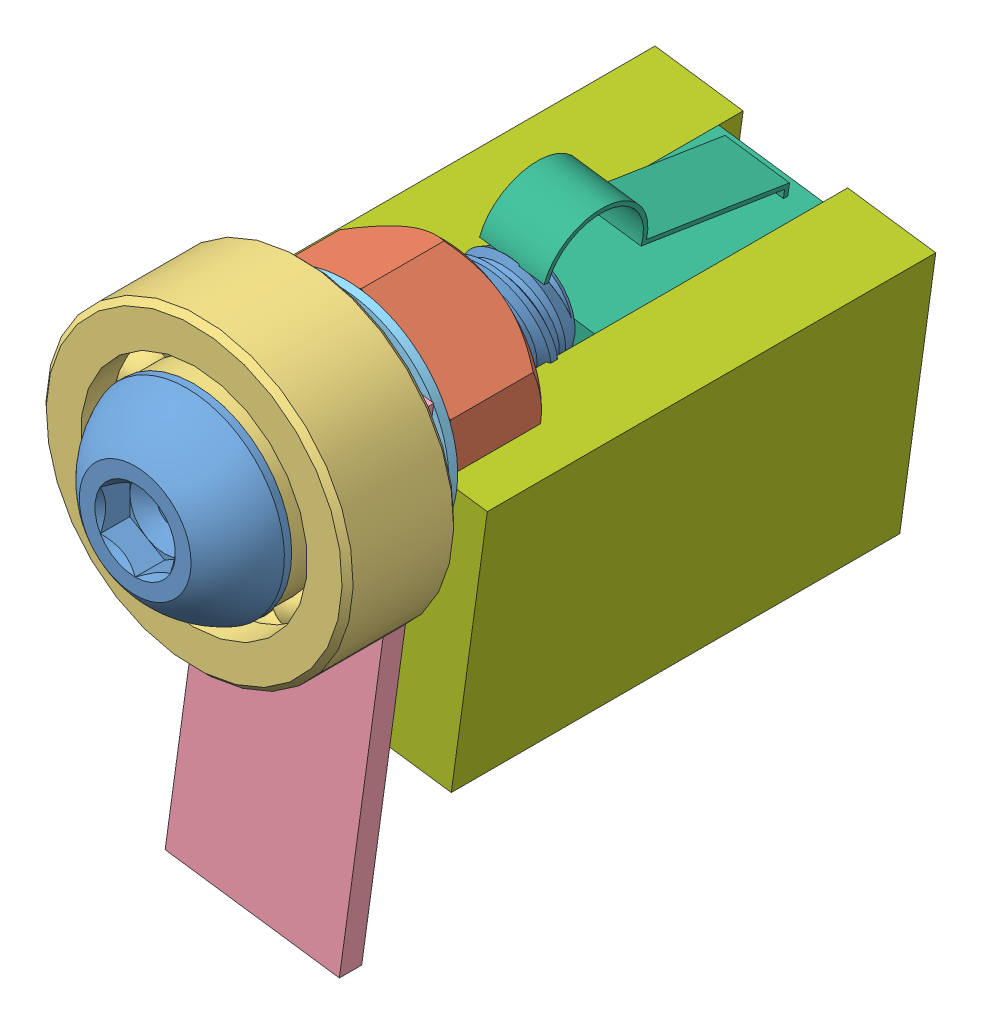
SolidWorks assembly Wall Bearing Assembly, configuration Default. Lengths in mm.
Overall size (24.27 38.57 37.77).
8 component instances, 7 part files, 15 mates.
Components (placement in the parent):
- Screw 1-4in 3-4in long-1: Screw 1-4in 3-4in long [91306A379] at (-1.5675 -0.0169 8.5729) size (11.1 11.1 22.63)
- Nut 1-4-20-1: Nut 1-4-20 [93827A211] at (-1.5675 -0.0169 -0.0631) x (-0.376986 0.926219 0) z (-0.926219 -0.376986 0) size (11.11 5.56 14.11)
- Bearing 1-4in ID 11-16in OD-1: Bearing 1-4in ID 11-16in OD [6383K12] at (-1.5675 -0.0169 5.3979) x (-0.826216 -0.563353 0) z (0 0 1) size (17.46 17.46 6.35)
- chassis arm-1: chassis arm [Default] at (3.9321 3.2624 1.7149) x (-0.990622 0.13663 0) z (-0.13663 -0.990622 0) size (10 1.27 30)
- Washer 0.26ID 0.5OD-1: Washer 0.26ID 0.5OD [98017A655] at (-1.5675 -0.0169 0.4449) x (0.900992 -0.433836 0) z (0 0 1) size (12.7 12.7 0.51)
- Washer 0.26ID 0.5OD-2: Washer 0.26ID 0.5OD [98017A655] at (-1.5675 -0.0169 2.2229) x (0.994237 -0.107202 0) z (0 0 1) size (12.7 12.7 0.51)
- Touch Sensor-1: Touch Sensor [Default] at (-2.0115 -3.2365 -17.7291) x (-0.13663 -0.990622 0) z (0.990622 -0.13663 0) size (11.99 15.15 6)
- Touch Sensor Holder-1: Touch Sensor Holder [Default] at (-1.5675 -0.0169 -0.1194) x (-0.13663 -0.990622 0) z (0.990622 -0.13663 0) size (15 25.5 16.11)
Mates (geometry in assembly coordinates):
- Concentric1: concentric anti-aligned: circle of Screw 1-4in 3-4in long-1; cylinder of Bearing 1-4in ID 11-16in OD-1 through (-1.5675 -0.0169 8.5729) axis (0 0 1) radius 3.175
- Concentric3: concentric anti-aligned: circle of Screw 1-4in 3-4in long-1; cylinder of chassis arm-1 through (-1.5675 -0.0169 0.4449) axis (0 0 1) radius 3.175
- Concentric5: concentric anti-aligned: circle of Screw 1-4in 3-4in long-1; circle of Nut 1-4-20-1
- Concentric6: concentric anti-aligned: circle of Screw 1-4in 3-4in long-1; cylinder of Washer 0.26ID 0.5OD-1 through (-1.5675 -0.0169 -0.0631) axis (0 0 1) radius 3.302
- Concentric7: concentric anti-aligned: circle of Screw 1-4in 3-4in long-1; cylinder of Washer 0.26ID 0.5OD-2 through (-1.5675 -0.0169 1.7149) axis (0 0 1) radius 3.302
- Coincident6: coincident anti-aligned: plane of Bearing 1-4in ID 11-16in OD-1 through (0.4 -2.9025 2.2229) normal (0 0 -1); plane of Washer 0.26ID 0.5OD-2 through (-1.5675 -0.0169 2.2229) normal (0 0 1)
- Coincident7: coincident anti-aligned: plane of chassis arm-1 through (3.9321 3.2624 1.7149) normal (0 0 1); plane of Washer 0.26ID 0.5OD-2 through (-1.5675 -0.0169 1.7149) normal (0 0 -1)
- Coincident8: coincident anti-aligned: plane of chassis arm-1 through (3.9321 3.2624 0.4449) normal (0 0 -1); plane of Washer 0.26ID 0.5OD-1 through (-1.5675 -0.0169 0.4449) normal (0 0 1)
- Coincident9: coincident anti-aligned: plane of Nut 1-4-20-1 through (9.4408 -1.5352 -0.0631) normal (0 0 1); plane of Washer 0.26ID 0.5OD-1 through (-1.5675 -0.0169 -0.0631) normal (0 0 -1)
- Coincident10: coincident anti-aligned: plane of Nut 1-4-20-1 through (9.4408 -1.5352 -5.6194) normal (0 0 -1); plane of Touch Sensor Holder-1 through (-1.5675 -0.0169 -5.6194) normal (0 0 1)
- Parallel1: parallel aligned: plane of chassis arm-1 through (3.9321 3.2624 0.4449) normal (0.990622 -0.13663 0); plane of Touch Sensor Holder-1 through (4.3637 -15.977 -5.6194) normal (0.990622 -0.13663 0)
- Coincident12: coincident anti-aligned: plane of Nut 1-4-20-1 through (4.3749 2.4017 -5.6194) normal (0.990622 -0.13663 0); plane of Touch Sensor Holder-1 through (3.9366 -0.7761 -5.6194) normal (-0.990622 0.13663 0)
- Coincident13: coincident anti-aligned: plane of Nut 1-4-20-1 through (-2.4441 -6.3726 -5.6194) normal (-0.613636 -0.789589 0); plane of Touch Sensor Holder-1 through (-2.4441 -6.3726 -5.6194) normal (0.613636 0.789589 0)
- Coincident14: coincident: plane of Touch Sensor-1 through (0.5163 -6.8659 -24.2291) normal (-0.13663 -0.990622 0); plane of Touch Sensor Holder-1 through (-2.4556 -6.456 -0.1194) normal (0.13663 0.990622 0)
- Coincident15: coincident anti-aligned: plane of Touch Sensor-1 through (-4.9834 -2.8266 -17.7291) normal (-0.990622 0.13663 0); plane of Touch Sensor Holder-1 through (-5.4275 -6.0461 -25.6194) normal (0.990622 -0.13663 0)
